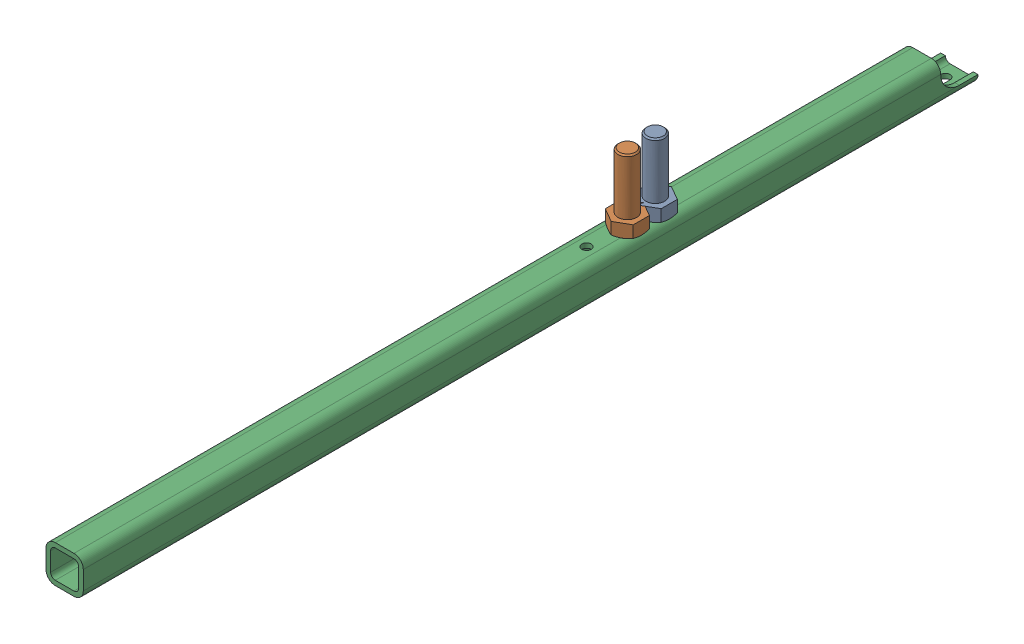
SolidWorks assembly 01-050-00-0, configuration Default. Lengths in mm.
Overall size (50.8 144.78 1219.2).
3 component instances, 2 part files, 0 mates.
Components (placement in the parent):
- hex bolt_ai(PreviewCfg)-1: hex bolt_ai(PreviewCfg) [Default] at (30.1625 50.8 -190.5) x (0 1 0) z (-1 0 0) size (93.98 43.99 38.1)
- hex bolt_ai(PreviewCfg)-2: hex bolt_ai(PreviewCfg) [Default] at (30.1625 50.8 -152.4) x (0 1 0) z (-1 0 0) size (93.98 43.99 38.1)
- 01-049-00-0-1: 01-049-00-0 [Default] at origin size (50.8 50.8 1219.2)
